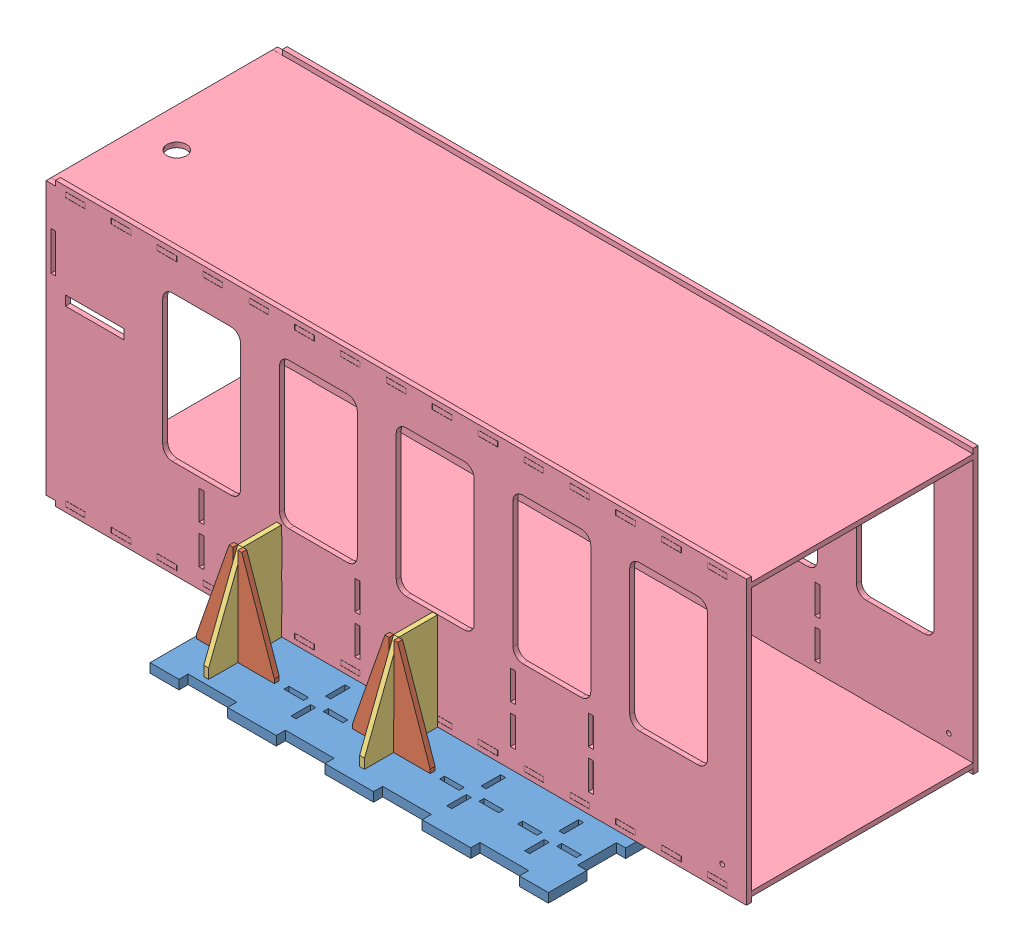
SolidWorks assembly Attachment_Assembly, configuration Position 1. Lengths in mm.
Overall size (457.2 190.36 266).
10 component instances, 4 part files, 30 mates.
Components (placement in the parent):
- Pillar Top R1.-1: Pillar Top R1. [Default] at (-81.9017 -8.7693 47.138)
- Bridge Attachment - Base-1: Bridge Attachment - Base [Default] at (-184.8761 -2.7693 -57.0782)
- Bridge Attachment - Top-1: Bridge Attachment - Top [Default] at (-183.3267 -2.7693 -28.7064) x (0 0 1) z (-1 0 0)
- Bridge Attachment - Base-2: Bridge Attachment - Base [Default] at (-184.8761 -2.7693 148.2554)
- Bridge Attachment - Top-2: Bridge Attachment - Top [Default] at (-186.5017 -2.7693 122.8554) x (0 0 -1) z (1 0 0)
- Bridge Attachment - Top-3: Bridge Attachment - Top [Default] at (-81.5997 -2.7693 -28.7064) x (0 0 1) z (-1 0 0)
- Bridge Attachment - Base-3: Bridge Attachment - Base [Default] at (-83.1491 -2.7693 148.2554)
- Bridge Attachment - Top-4: Bridge Attachment - Top [Default] at (-84.7747 -2.7693 122.8554) x (0 0 -1) z (1 0 0)
- Bridge Attachment - Base-4: Bridge Attachment - Base [Default] at (-83.1491 -2.7693 -57.0782)
- LargeBox-1: LargeBox [BoxLevel=1] at (-337.2507 0.5089 119.528)
Mates (geometry in assembly coordinates):
- Coincident1: coincident anti-aligned: plane of Pillar Top R1.-1 through (-186.5017 -8.7693 -57.2052) normal (1 0 0); plane of Bridge Attachment - Top-1 through (-186.5017 -2.7693 -28.7064) normal (-1 0 0)
- Coincident2: coincident anti-aligned: plane of Pillar Top R1.-1 through (-186.5017 -8.7693 -69.9814) normal (0 0 1); plane of Bridge Attachment - Top-1 through (-186.5017 -6.5793 -69.9814) normal (0 0 -1)
- Coincident4: coincident anti-aligned: plane of Pillar Top R1.-1 through (-191.2261 -8.7693 -53.9032) normal (0 0 -1); plane of Bridge Attachment - Base-1 through (-184.8761 -2.7693 -53.9032) normal (0 0 1)
- Coincident5: coincident: plane of Pillar Top R1.-1 through (-81.9017 -2.7693 47.138) normal (0 1 0); line of Bridge Attachment - Base-1 through (-165.8261 -2.7693 -57.0782) axis (1 0 0)
- Coincident6: coincident anti-aligned: plane of Pillar Top R1.-1 through (-191.2261 -8.7693 151.4304) normal (0 0 -1); plane of Bridge Attachment - Base-2 through (-184.8761 -2.7693 151.4304) normal (0 0 1)
- Coincident8: coincident aligned: plane of Bridge Attachment - Base-1 through (-186.5017 16.1537 -53.9032) normal (1 0 0); plane of Bridge Attachment - Base-2 through (-186.5017 16.1537 151.4304) normal (1 0 0)
- Coincident9: coincident anti-aligned: plane of Pillar Top R1.-1 through (-81.9017 -2.7693 47.138) normal (0 1 0); plane of Bridge Attachment - Base-2 through (-184.8761 -2.7693 151.4304) normal (0 -1 0)
- Coincident10: coincident aligned: plane of Bridge Attachment - Top-1 through (-183.3267 -2.7693 -28.7064) normal (1 0 0); plane of Bridge Attachment - Top-2 through (-183.3267 -2.7693 122.8554) normal (1 0 0)
- Coincident11: coincident aligned: plane of Bridge Attachment - Top-1 through (-186.5017 60.7307 -28.7064) normal (0 1 0); plane of Bridge Attachment - Top-2 through (-183.3267 60.7307 122.8554) normal (0 1 0)
- Coincident12: coincident anti-aligned: plane of Bridge Attachment - Base-2 through (-184.8761 -2.7693 148.2554) normal (0 0 -1); plane of Bridge Attachment - Top-2 through (-183.3267 -2.7693 148.2554) normal (0 0 1)
- Coincident13: coincident anti-aligned: plane of Pillar Top R1.-1 through (-81.9017 -2.7693 47.138) normal (0 1 0); plane of Bridge Attachment - Top-2 through (-183.3267 -2.7693 141.9054) normal (0 -1 0)
- Coincident14: coincident anti-aligned: plane of Bridge Attachment - Base-3 through (-83.1491 -2.7693 148.2554) normal (0 0 -1); plane of Bridge Attachment - Top-4 through (-81.5997 -2.7693 148.2554) normal (0 0 1)
- Coincident15: coincident aligned: plane of Bridge Attachment - Top-3 through (-84.7747 60.7307 -28.7064) normal (0 1 0); plane of Bridge Attachment - Top-4 through (-81.5997 60.7307 122.8554) normal (0 1 0)
- Coincident16: coincident aligned: plane of Bridge Attachment - Base-3 through (-84.7747 16.1537 151.4304) normal (1 0 0); plane of Bridge Attachment - Base-4 through (-84.7747 16.1537 -53.9032) normal (1 0 0)
- Coincident17: coincident aligned: plane of Bridge Attachment - Top-3 through (-81.5997 -2.7693 -28.7064) normal (1 0 0); plane of Bridge Attachment - Top-4 through (-81.5997 -2.7693 122.8554) normal (1 0 0)
- Coincident18: coincident anti-aligned: plane of Pillar Top R1.-1 through (-81.9017 -2.7693 47.138) normal (0 1 0); plane of Bridge Attachment - Base-4 through (-83.1491 -2.7693 -53.9032) normal (0 -1 0)
- Coincident20: coincident aligned: plane of Bridge Attachment - Base-1 through (-184.8761 -2.7693 -53.9032) normal (0 0 1); plane of Bridge Attachment - Base-4 through (-83.1491 -2.7693 -53.9032) normal (0 0 1)
- Coincident21: coincident aligned: plane of Bridge Attachment - Base-2 through (-184.8761 -2.7693 151.4304) normal (0 0 1); plane of Bridge Attachment - Base-3 through (-83.1491 -2.7693 151.4304) normal (0 0 1)
- Coincident22: coincident aligned: plane of Bridge Attachment - Top-2 through (-183.3267 -2.7693 170.4804) normal (0 0 1); plane of Bridge Attachment - Top-4 through (-81.5997 -2.7693 170.4804) normal (0 0 1)
- Coincident23: coincident aligned: plane of Bridge Attachment - Top-2 through (-183.3267 60.7307 122.8554) normal (0 1 0); plane of Bridge Attachment - Top-4 through (-81.5997 60.7307 122.8554) normal (0 1 0)
- Coincident24: coincident aligned: plane of Bridge Attachment - Top-1 through (-186.5017 54.3807 -25.6584) normal (0 0 1); plane of Bridge Attachment - Top-3 through (-84.7747 54.3807 -25.6584) normal (0 0 1)
- Coincident26: coincident aligned: plane of Bridge Attachment - Base-2 through (-183.2505 60.7307 151.4304) normal (0 1 0); plane of Bridge Attachment - Base-3 through (-81.5235 60.7307 151.4304) normal (0 1 0)
- Coincident27: coincident anti-aligned: plane of Pillar Top R1.-1 through (-81.9017 -2.7693 47.138) normal (0 1 0); plane of LargeBox-1 through (124.4395 -2.7693 119.528) normal (0 -1 0)
- Coincident28: coincident anti-aligned: plane of LargeBox-1 through (-337.2507 0.5089 47.138) normal (0 0 -1)
- Coincident29: coincident anti-aligned: plane of Bridge Attachment - Top-2 through (-186.5017 -2.7693 122.8554) normal (-1 0 0); plane of LargeBox-1 through (-186.5017 54.368 -28.427) normal (1 0 0)
- Coincident30: coincident anti-aligned: plane of Bridge Attachment - Top-4 through (-81.5997 -2.7693 122.8554) normal (1 0 0); plane of LargeBox-1 through (-81.5997 54.368 -28.427) normal (-1 0 0)
- Coincident31: coincident anti-aligned: plane of Pillar Top R1.-1 through (-132.4505 -8.7693 -57.2052) normal (-1 0 0); plane of Bridge Attachment - Top-1 through (-132.4505 -2.7693 -28.7064) normal (1 0 0)
- Coincident32: coincident anti-aligned: plane of Bridge Attachment - Base-1 through (-186.5017 16.1537 -53.9032) normal (1 0 0); plane of Bridge Attachment - Top-1 through (-186.5017 -2.7693 -28.7064) normal (-1 0 0)
- Coincident33: coincident anti-aligned: plane of Bridge Attachment - Top-3 through (-84.7747 -2.7693 -28.7064) normal (-1 0 0); plane of Bridge Attachment - Base-4 through (-84.7747 16.1537 -53.9032) normal (1 0 0)
- Coincident34: coincident anti-aligned: plane of Pillar Top R1.-1 through (-81.6505 -8.7693 -57.2052) normal (-1 0 0); plane of Bridge Attachment - Top-1 through (-81.6505 -2.7693 -28.7064) normal (1 0 0)
